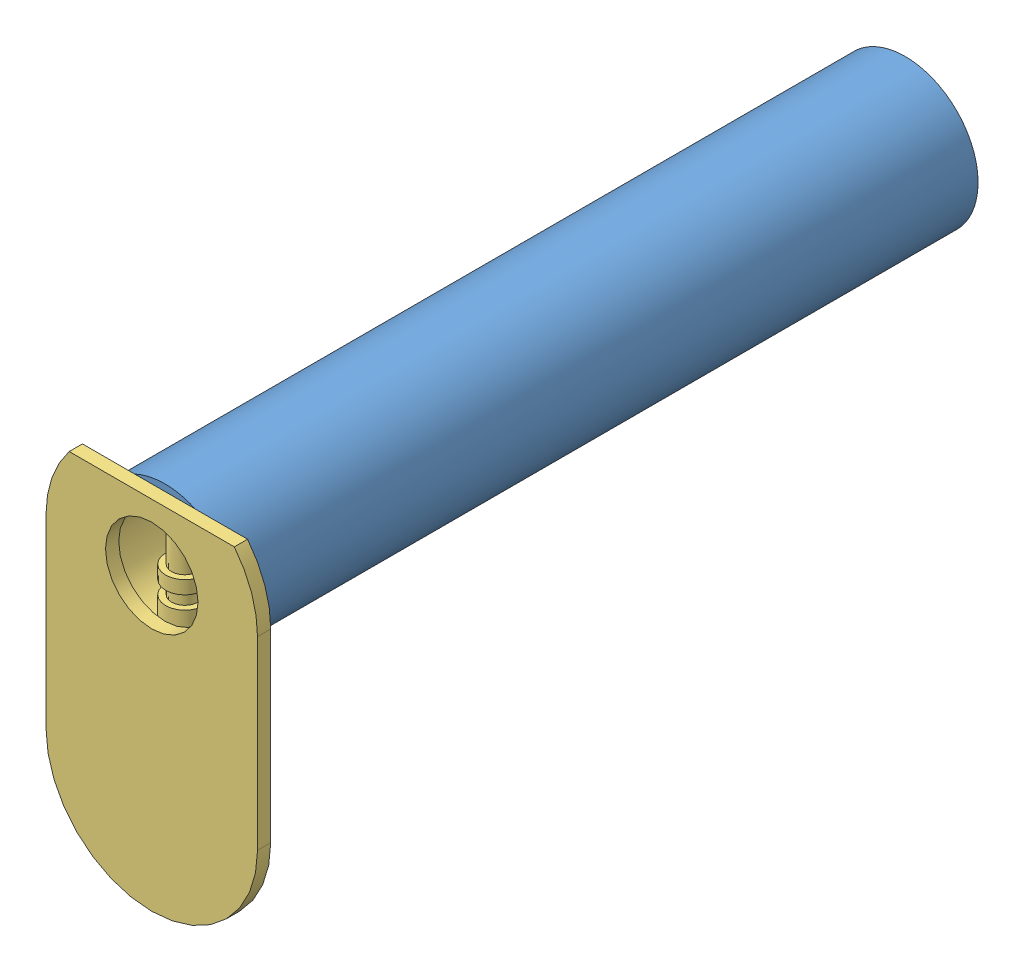
SolidWorks assembly 141 Verin, configuration Rentré. Lengths in mm.
Overall size (16 27.5 58.3).
8 component instances, 4 part files, 19 mates.
Components (placement in the parent):
- 142 Verin tube 1-1: 142 Verin tube 1 [Défaut] at origin size (11 11 56)
- 143 Verin tube 2-1: 143 Verin tube 2 [Défaut] at origin size (10 10 56)
- 144 Verin tube 3-1: 144 Verin tube 3 [Défaut] at origin size (16 27 57)
- 145 Poulie verin-1: 145 Poulie verin [Défaut] at (0 2 23) x (0 -1 0) z (0.145903 0 0.989299) size (2 4 4)
- 145 Poulie verin-2: 145 Poulie verin [Défaut] at (0 0 19.5) x (0 1 0) z (0.678653 0 -0.734459) size (2 4 4)
- 145 Poulie verin-3: 145 Poulie verin [Défaut] at (0 2 -27) x (0 -1 0) z (0.16644 0 0.986052) size (2 4 4)
- 145 Poulie verin-4: 145 Poulie verin [Défaut] at (0 0 -27) x (0 -1 0) z (0.16644 0 0.986052) size (2 4 4)
- 145 Poulie verin-5: 145 Poulie verin [Défaut] at (0 -2 -27) x (0 -1 0) z (0.16644 0 0.986052) size (2 4 4)
Mates (geometry in assembly coordinates):
- Coaxiale1: concentric aligned: cylinder of 142 Verin tube 1-1 through (0 0 28) axis (0 0 -1) radius 5; cylinder of 143 Verin tube 2-1 through (0 0 28) axis (0 0 -1) radius 5
- Coaxiale2: concentric aligned: cylinder of 143 Verin tube 2-1 through (0 0 28) axis (0 0 -1) radius 5; cylinder of 144 Verin tube 3-1 through (0 0 28) axis (0 0 -1) radius 4.5
- Coïncidente1: coordinate: point of ?
- Coïncidente2: coincident aligned: plane of 143 Verin tube 2-1 through (0 0 0) normal (0 1 0); plane of 144 Verin tube 3-1 through (0 0 0) normal (0 1 0)
- Coïncidente3: coincident aligned: plane of 142 Verin tube 1-1 through (0 0 0) normal (0 1 0); plane of 143 Verin tube 2-1 through (0 0 0) normal (0 1 0)
- Distance1: distance = 9 mm anti-aligned: plane of 143 Verin tube 2-1 through (0 0 62) normal (0 0 1); plane of 144 Verin tube 3-1 through (0 0 53) normal (0 0 -1)
- Coïncidente4: coincident aligned: plane of 142 Verin tube 1-1 through (0 0 -28) normal (0 0 -1); plane of 143 Verin tube 2-1 through (0 0 -28) normal (0 0 -1)
- Coïncidente5: coincident aligned: plane of 143 Verin tube 2-1 through (0 0 -28) normal (0 0 -1); plane of 144 Verin tube 3-1 through (0 0 -28) normal (0 0 -1)
- Coaxiale3: concentric aligned: cylinder of 143 Verin tube 2-1 through (0 -500000 23) axis (0 1 0) radius 1; cylinder of 145 Poulie verin-1 through (0 3.3499 23) axis (0 1 0) radius 1
- Coaxiale4: concentric anti-aligned: cylinder of 142 Verin tube 1-1 through (0 -500000 19.5) axis (0 1 0) radius 1; cylinder of 145 Poulie verin-2 through (0 -1.3499 19.5) axis (0 -1 0) radius 1
- Coïncidente7: coincident aligned: plane of 145 Poulie verin-2; plane of assembly through (0 0 0) normal (0 1 0)
- Coïncidente8: coincident anti-aligned: plane of 145 Poulie verin-4 through (1.9721 -1 -27.3329) normal (0 -1 0); plane of 145 Poulie verin-5 through (1.9721 -1 -27.3329) normal (0 1 0)
- Coïncidente9: coincident anti-aligned: plane of 145 Poulie verin-3 through (1.9721 1 -27.3329) normal (0 -1 0); plane of 145 Poulie verin-4 through (1.9721 1 -27.3329) normal (0 1 0)
- Coaxiale5: concentric aligned: cylinder of 142 Verin tube 1-1 through (0 -500000 -27) axis (0 1 0) radius 1; cylinder of 145 Poulie verin-5 through (0 -0.6501 -27) axis (0 1 0) radius 1
- Coaxiale6: concentric aligned: cylinder of 142 Verin tube 1-1 through (0 -500000 -27) axis (0 1 0) radius 1; cylinder of 145 Poulie verin-4 through (0 1.3499 -27) axis (0 1 0) radius 1
- Coaxiale7: concentric aligned: cylinder of 142 Verin tube 1-1 through (0 -500000 -27) axis (0 1 0) radius 1; cylinder of 145 Poulie verin-3 through (0 3.3499 -27) axis (0 1 0) radius 1
- Coïncidente10: coincident anti-aligned: plane of 145 Poulie verin-4; plane of assembly through (0 0 0) normal (0 1 0)
- Coïncidente11: coincident anti-aligned: plane of 145 Poulie verin-1 through (1.9786 1 22.7082) normal (0 -1 0); plane of 145 Poulie verin-2 through (1.4689 1 20.8573) normal (0 1 0)
- Coaxiale9: concentric aligned: cylinder of 142 Verin tube 1-1 through (0 -500000 18.5) axis (0 1 0) radius 1; cylinder of 143 Verin tube 2-1 through (0 -5 18.5) axis (0 1 0) radius 1
